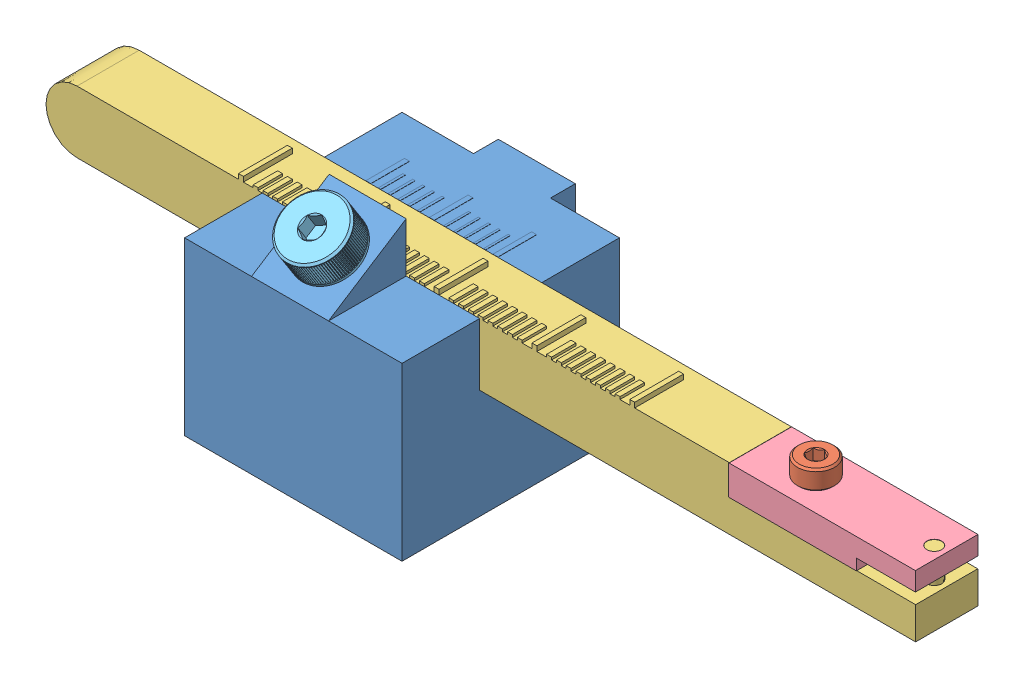
SolidWorks assembly headbar finished assem, configuration Default. Lengths in mm.
Overall size (88.9 24.55 25.25).
6 component instances, 5 part files, 4 mates.
Components (placement in the parent):
- bar rest-1: bar rest [Default] at origin size (22.23 22.61 24.77)
- 91292A003_TYPE 18-8 SS SOCKET HEAD CAP SCREW-1: 91292A003_TYPE 18-8 SS SOCKET HEAD CAP SCREW [91292A003] at (53.4332 5.7455 0) x (1 0 0) z (0 -1 0) size (3.8 3.8 5.09)
- headbar-1: headbar [Default] at (115.3465 -57.3797 -49.0764) x (0 0 1) z (-1 0 0) size (6.4 6.86 88.9)
  - headpost holder-1: headpost holder [Default] at (49.0764 62.9677 48.5529) x (0 1 0) z (0 0 1) size (6.86 6.35 88.9)
  - headbar clamp-1: headbar clamp [Default] at (49.0764 64.2202 58.1033) x (0 0 1) z (-1 0 0) size (19.1 3.05 6.4)
- 96125A301_NICKEL ALLOY SHOULDER SCREW-1: 96125A301_NICKEL ALLOY SHOULDER SCREW [96125A301] at (10.7798 13.9746 8.8593) x (1 0 0) z (0 0.842271 0.539054) size (6.35 6.35 10.69)
Mates (geometry in assembly coordinates):
- Concentric4: concentric anti-aligned: circle of 91292A003_TYPE 18-8 SS SOCKET HEAD CAP SCREW-1; circle of headbar-1/headbar clamp-1
- Coincident3: coincident anti-aligned: plane of 91292A003_TYPE 18-8 SS SOCKET HEAD CAP SCREW-1 through (53.4332 8.7455 0) normal (0 -1 0); plane of headbar-1/headbar clamp-1 through (57.2432 8.7455 0) normal (0 1 0)
- Concentric5: concentric anti-aligned: cylinder of bar rest-1 through (10.7798 11.3004 7.1478) axis (0 0.842271 0.539054) radius 2.5527; circle of 96125A301_NICKEL ALLOY SHOULDER SCREW-1
- Coincident5: coincident anti-aligned: plane of bar rest-1 through (-0.001 8.763 11.1125) normal (0 0.842271 0.539054); plane of 96125A301_NICKEL ALLOY SHOULDER SCREW-1 through (10.7798 9.5889 9.822) normal (0 -0.842271 -0.539054)
